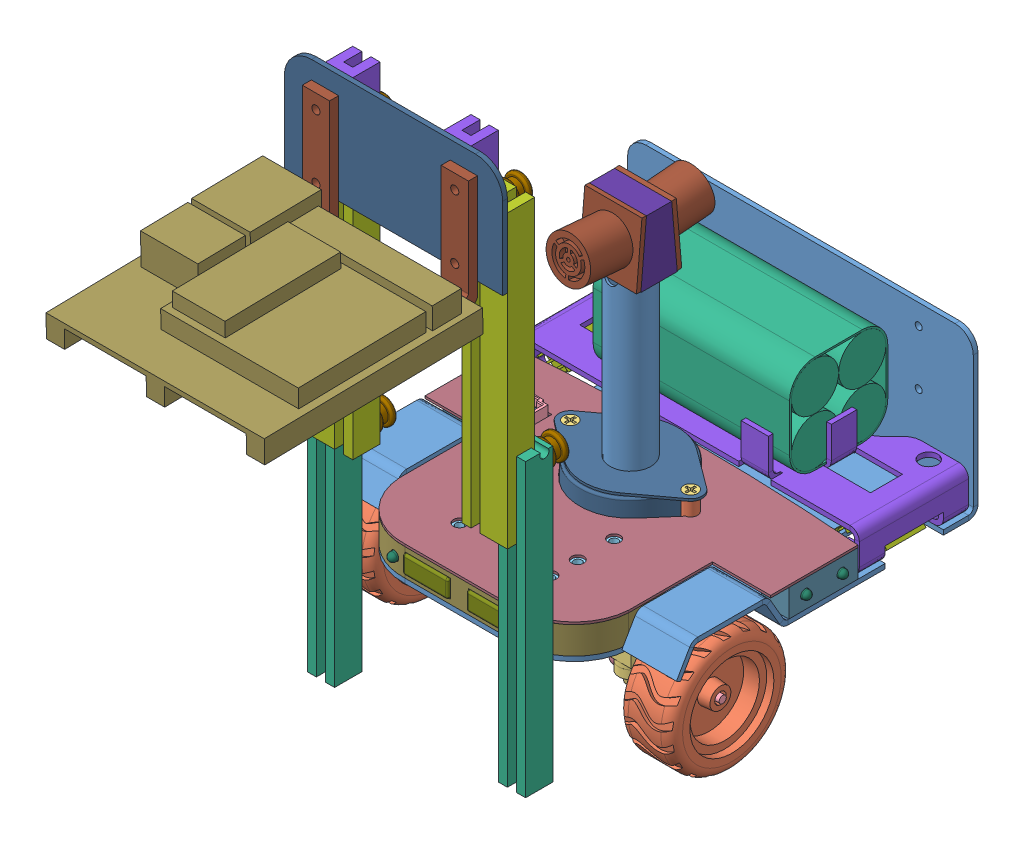
SolidWorks assembly FORKLIFT, TEST ASSEMBLY, configuration Default. Lengths in mm.
Overall size (124.43 199.42 225.89).
61 component instances, 30 part files, 5 mates.
Components (placement in the parent):
- REAR, TOP LEVEL-1: REAR, TOP LEVEL [Default] at (5.4266 -37.4478 22.578) size (124.43 133.68 122.55)
  - PLATE, REAR-1: PLATE, REAR [Default] at (-42.1312 28.0774 12.7174) size (120.65 55.63 120.66)
  - WHEEL ASSEMBLY-1: WHEEL ASSEMBLY [Default-_flexible1] at (7.6153 26.9792 58.7651) x (0 0 1) z (1 0 0) size (42.46 78.6 70.03) (flexible)
    - Pololu 49x19 Wheel-1: Pololu 49x19 Wheel [Default] at (-19.8703 11.8393 2.4418) size (42.46 42.56 19)
    - Pololu Extended Micro Metal Bracket-1: Pololu Extended Micro Metal Bracket [Default] at (-19.8703 6.8393 -18.4366) size (26.6 22.49 26.04)
    - Pololu 298-1 Motor-1: Pololu 298-1 Motor [Default] at (-19.8703 11.8393 -25.1366) x (0 0 -1) z (0 1 0) size (35.87 12 10)
  - WHEEL ASSEMBLY-2: WHEEL ASSEMBLY [Default-_flexible2] at (-91.8778 26.9792 19.0244) x (0 0 -1) z (-1 0 0) size (42.46 78.6 70.03) (flexible)
    - Pololu 49x19 Wheel-1: Pololu 49x19 Wheel [Default] at (-19.8703 11.8393 2.4418) size (42.46 42.56 19)
    - Pololu Extended Micro Metal Bracket-1: Pololu Extended Micro Metal Bracket [Default] at (-19.8703 6.8393 -18.4366) size (26.6 22.49 26.04)
    - Pololu 298-1 Motor-1: Pololu 298-1 Motor [Default] at (-19.8703 11.8393 -25.1366) x (0 0 -1) z (0 1 0) size (35.87 12 10)
  - Socket Head Cap Screw_AI-1: Socket Head Cap Screw_AI [HX-SHCS 0.086-56x0.4375x0.4375-N] at (-77.6912 31.9128 47.8948) x (0 -1 0) z (-0.381305 0 -0.924449) size (13.3 3.56 3.56)
  - Socket Head Cap Screw_AI-2: Socket Head Cap Screw_AI [HX-SHCS 0.086-56x0.4375x0.4375-N] at (-77.6912 31.9128 29.8948) x (0 -1 0) z (0 0 1) size (13.3 3.56 3.56)
  - Socket Head Cap Screw_AI-3: Socket Head Cap Screw_AI [HX-SHCS 0.086-56x0.4375x0.4375-N] at (-6.5712 31.9128 29.8948) x (0 -1 0) z (0 0 1) size (13.3 3.56 3.56)
  - Socket Head Cap Screw_AI-4: Socket Head Cap Screw_AI [HX-SHCS 0.086-56x0.4375x0.4375-N] at (-6.5712 31.9128 47.8948) x (0 -1 0) z (0 0 1) size (13.3 3.56 3.56)
  - 4000mAh 7.4V Battery Pack-1: 4000mAh 7.4V Battery Pack [Default] at (-42.1312 61.2244 -25.7652) x (0 0 -1) z (1 0 0) size (34.29 34.29 68.58)
  - SENSOR, GP2Y0D810-1: SENSOR, GP2Y0D810 [Default] at (9.9271 36.6454 -23.9555) x (0 0 -1) z (0.766044 0.642788 0) size (28.32 10.54 8.89)
  - SENSOR, GP2Y0D810-2: SENSOR, GP2Y0D810 [Default] at (-94.1896 36.6454 -23.9555) x (0 0 -1) z (0.766044 -0.642788 0) size (28.32 10.54 8.89)
  - Battery Support-1: Battery Support [Default] at (-42.1312 29.7284 -26.0192) size (120.65 27.05 38.1)
  - Mounting Block-1: Mounting Block [Default] at (-42.1312 36.0784 -35.6712) x (-1 0 0) z (0 0 -1) size (25.4 12.7 25.4)
  - PF35T-48-1: PF35T-48 [Default] at (-42.1312 31.7284 12.5888) size (50 29.2 35)
  - MaxSonar EZ1-1: MaxSonar EZ1 [Default] at (-42.1312 115.1044 7.2202) x (-1 0 0) z (0 0.087156 -0.996195) size (19.94 22.1 16.38)
  - MaxSonar EZ1-2: MaxSonar EZ1 [Default] at (-42.1312 115.1044 17.9573) x (1 0 0) z (0 0.087156 0.996195) size (19.94 22.1 16.38)
  - BUMPER, REAR-1: BUMPER, REAR [Default] at (-42.1312 29.7284 53.2288) x (-1 0 0) z (0 0 -1) size (80.01 9.53 31.76)
  - PLATE, REAR COVER-1: PLATE, REAR COVER [Default] at (-42.1312 39.2534 72.2788) size (120.65 0.81 81.14)
  - MOUNTING BLOCK, COLOR SENSOR-1: MOUNTING BLOCK, COLOR SENSOR [Default] at (-97.6937 29.7284 5.6038) size (9.53 9.53 24.13)
  - MOUNTING BLOCK, COLOR SENSOR-2: MOUNTING BLOCK, COLOR SENSOR [Default] at (13.4313 29.7284 5.6038) size (9.53 9.53 24.13)
  - SENSOR, COLOR LED-1: SENSOR, COLOR LED [Default] at (-27.6486 42.7147 33.8533) x (0 0 -1) z (-0.713616 0.700538 0) size (5.83 3.66 3.66)
  - SENSOR, COLOR LED-2: SENSOR, COLOR LED [Default] at (-64.9673 22.7516 33.8533) x (0 0 -1) z (0.002041 -0.999998 0) size (5.83 3.66 3.66)
  - COPPER CONTACT-1: COPPER CONTACT [Default] at (-53.2437 34.4909 66.8178) size (15.88 6.35 6.35)
  - COPPER CONTACT-2: COPPER CONTACT [Default] at (-31.0187 34.4909 66.8178) size (15.88 6.35 6.35)
  - MOUNTING BLOCK, SONAR-1: MOUNTING BLOCK, SONAR [Default] at (-42.1312 114.9989 12.5888) x (-1 0 0) z (0 0 -1) size (19.94 22.23 12.7)
  - SHAFT, SONAR MOUNT-1: SHAFT, SONAR MOUNT [Default] at (-42.1312 52.5784 12.5888) x (-0.538443 0 0.842662) z (-0.842662 0 -0.538443) size (4.76 64.01 4.76)
  - SHAFT, SONAR SUPPORT-1: SHAFT, SONAR SUPPORT [Default] at (-42.1312 46.7284 12.5888) x (0.999987 0 0.005105) z (-0.005105 0 0.999987) size (14.22 57.47 14.22)
  - SHAFT, STEPPER SUPPORT-1: SHAFT, STEPPER SUPPORT [Default] at (-63.1312 29.6724 12.5888) size (4.76 16.26 4.76)
  - SHAFT, STEPPER SUPPORT-2: SHAFT, STEPPER SUPPORT [Default] at (-21.1312 29.6724 12.5888) x (0.987866 0 -0.155311) z (0.155311 0 0.987866) size (4.76 16.26 4.76)
  - Flat Head 100 Screw_AI-2: Flat Head 100 Screw_AI [CR-FHM1 0.112-40x0.25x0.25-N] at (-63.1312 46.7284 12.5888) x (0 -1 0) z (0 0 1) size (6.35 4.85 4.85)
  - Flat Head 100 Screw_AI-3: Flat Head 100 Screw_AI [CR-FHM1 0.112-40x0.25x0.25-N] at (-21.1312 46.7284 12.5888) x (0 -1 0) z (0 0 1) size (6.35 4.85 4.85)
  - CONNECTOR, MOLEX 6 PIN-1: CONNECTOR, MOLEX 6 PIN [Default] at (-80.2263 37.7912 12.5433) size (10.34 13.8 9.75)
  - SENSOR, COLOR LED-3: SENSOR, COLOR LED [Default] at (-64.0196 42.7147 3.5765) x (1 0 0) z (0 0.700538 -0.713616) size (5.83 3.66 3.66)
  - SENSOR, COLOR LED-4: SENSOR, COLOR LED [Default] at (-64.0196 42.7147 -9.1235) x (1 0 0) z (0 0.700538 -0.713616) size (5.83 3.66 3.66)
  - SENSOR, COLOR LED-5: SENSOR, COLOR LED [Default] at (-20.2429 42.7147 20.3311) x (-1 0 0) z (0 0.700538 0.713616) size (5.83 3.66 3.66)
  - SENSOR, COLOR LED-6: SENSOR, COLOR LED [Default] at (-20.2429 42.7147 7.6311) x (-1 0 0) z (0 0.700538 0.713616) size (5.83 3.66 3.66)
  - MOUNTING BLOCK, REAR-1: MOUNTING BLOCK, REAR [Default] at (-58.0062 34.4909 29.4163) size (9.53 9.53 31.75)
  - MOUNTING BLOCK, REAR-2: MOUNTING BLOCK, REAR [Default] at (-26.2562 34.4909 29.4163) size (9.53 9.53 31.75)
- FORKLIFT, SLIDE TOP ASSEMBLY-1: FORKLIFT, SLIDE TOP ASSEMBLY [Default] at (-14.5545 14.3637 112.1089) x (-1 0 0) z (0 0 -1) size (76.2 193.85 96.9)
  - FORKLIFT, SECTION A-1: FORKLIFT, SECTION A [Default] at (-11.1873 -1.5853 6.9805) size (9.53 101.6 9.53)
  - FORKLIFT, SECTION B-1: FORKLIFT, SECTION B [Default] at (-4.8373 73.5867 3.8055) size (15.88 101.6 9.53)
  - FORKLIFT, SECTION C-1: FORKLIFT, SECTION C [Default] at (1.5127 122.418 0.6305) size (9.53 38.1 9.53)
  - FORKLIFT, SLIDE PULLEY-1: FORKLIFT, SLIDE PULLEY [Default] at (-11.1873 44.1347 9.203) size (8.89 8.89 8.89)
  - FORKLIFT, SLIDE PULLEY-2: FORKLIFT, SLIDE PULLEY [Default] at (-1.6623 27.8667 6.028) x (0.950689 -0.310147 0) z (0 0 1) size (8.89 8.89 8.89)
  - FORKLIFT, SECTION A-2: FORKLIFT, SECTION A [Default] at (55.4877 -1.5853 6.9805) size (9.53 101.6 9.53)
  - FORKLIFT, SECTION B-2: FORKLIFT, SECTION B [Default] at (49.1377 73.5867 3.8055) x (-1 0 0) z (0 0 1) size (15.88 101.6 9.53)
  - FORKLIFT, SECTION C-2: FORKLIFT, SECTION C [Default] at (42.7877 122.418 0.6305) size (9.53 38.1 9.53)
  - FORKLIFT, SLIDE PULLEY-3: FORKLIFT, SLIDE PULLEY [Default] at (45.9627 27.8667 6.028) size (8.89 8.89 8.89)
  - FORKLIFT, SLIDE PULLEY-4: FORKLIFT, SLIDE PULLEY [Default] at (55.4877 44.1347 9.203) size (8.89 8.89 8.89)
  - FORKLIFT, CARRIAGE, BACKPLATE-1: FORKLIFT, CARRIAGE, BACKPLATE [Default] at (22.1502 122.418 -5.783) size (76.2 38.1 1.65)
  - FORKLIFT, TINE-1: FORKLIFT, TINE [Default] at (-2.3975 97.1379 -8.958) x (0 0 -1) z (1 0 0) size (73.02 38.1 9.53)
  - FORKLIFT, TINE-2: FORKLIFT, TINE [Default] at (46.0584 97.1379 -8.958) x (0 0 -1) z (1 0 0) size (73.02 38.1 9.53)
  - FORKLIFT, SLIDE PULLEY-5: FORKLIFT, SLIDE PULLEY [Default] at (-1.6623 119.3067 6.028) size (8.89 8.89 8.89)
  - FORKLIFT, SLIDE PULLEY-6: FORKLIFT, SLIDE PULLEY [Default] at (45.9627 119.3067 6.028) size (8.89 8.89 8.89)
- Pallet-1: Pallet [Default] at (-37.9202 111.551 123.595) x (1 0 0) z (0 -0.019604 0.999808) size (76.2 19.43 76.2)
Mates (geometry in assembly coordinates):
- Parallel1: parallel aligned: plane of REAR, TOP LEVEL-1/COPPER CONTACT-2 through (-17.6547 0.2181 95.7457) normal (0 0 1); plane of FORKLIFT, SLIDE TOP ASSEMBLY-1/FORKLIFT, SECTION B-2 through (-71.6297 37.1504 113.066) normal (0 0 1)
- Coincident1: coincident anti-aligned: plane of REAR, TOP LEVEL-1/PLATE, REAR-1 through (-36.7047 -9.3704 35.2954) normal (1 0 0); plane of FORKLIFT, SLIDE TOP ASSEMBLY-1/FORKLIFT, CARRIAGE, BACKPLATE-1 through (-36.7047 136.7818 117.892) normal (-1 0 0)
- Coincident2: coincident anti-aligned: plane of FORKLIFT, SLIDE TOP ASSEMBLY-1/FORKLIFT, TINE-2 through (-65.3754 114.6766 126.147) normal (0 0.999808 0.019604); plane of Pallet-1 through (-37.9202 113.2316 199.8426) normal (0 -0.999808 -0.019604)
- Distance2: distance = 8.89 mm: line of FORKLIFT, SLIDE TOP ASSEMBLY-1/FORKLIFT, TINE-2; plane of Pallet-1 through (-37.9202 51.1571 198.6254) normal (0 -0.019604 0.999808)
- Distance3: distance = 40.64 mm anti-aligned: plane of FORKLIFT, SLIDE TOP ASSEMBLY-1/FORKLIFT, SECTION A-1 through (-8.1297 -38.0216 109.891) normal (0 -1 0); plane of REAR, TOP LEVEL-1/PLATE, REAR COVER-1 through (-56.4287 2.6184 74.5479) normal (0 1 0)
